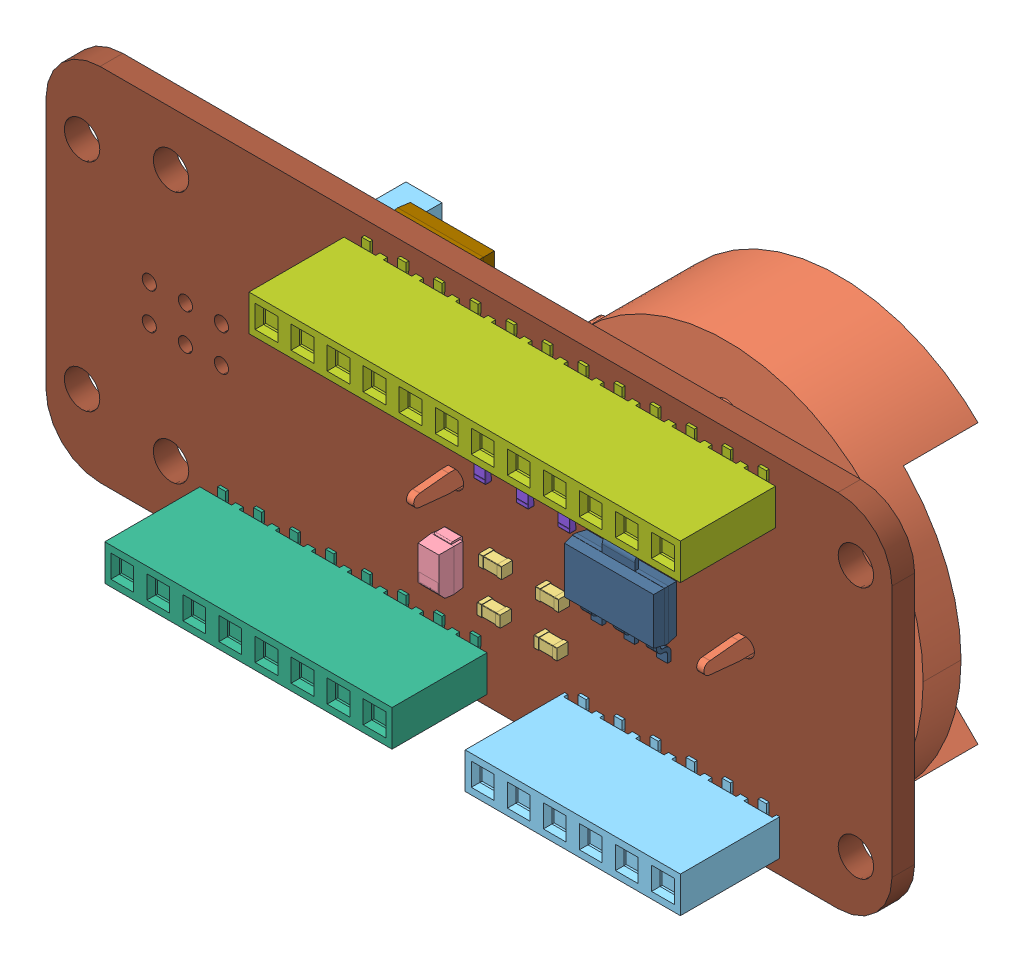
SolidWorks assembly p21014, configuration Default. Lengths in mm.
Overall size (59.61 27.76 20.34).
44 component instances, 11 part files, 0 mates.
Components (placement in the parent):
- p21014.step-1: p21014.step [Default] at origin size (59.61 27.76 20.34)
  - LED_0805_2012Metric.step-1: LED_0805_2012Metric.step [Default] at (193.91 -69.95 -0.05) x (1 0 0) z (0 0 -1) size (2 1.25 1.1)
    - SOLID.step-1: SOLID.step [Default] at origin size (2 1.25 1.1)
  - keystone-PN1027.step-1: keystone-PN1027.step [Default] at (211 -60.16 -2.55) x (0 1 0) z (-1 0 0) size (27.76 16.03 30.96)
    - SOLID-0.step-1: SOLID-0.step [Default] at origin size (27.76 16.03 30.96)
  - C_0603_1608Metric.step-1: C_0603_1608Metric.step [Default] at (203.265 -66.415 1.65) size (1.6 0.8 0.8)
    - SOLID-1.step-1: SOLID-1.step [Default] at origin size (1.6 0.8 0.8)
  - C_0603_1608Metric.step-2: C_0603_1608Metric.step [Default] at (203.365 -63.405 1.65) size (1.6 0.8 0.8)
    - SOLID-1.step-1: SOLID-1.step [Default] at origin size (1.6 0.8 0.8)
  - C_0603_1608Metric.step-3: C_0603_1608Metric.step [Default] at (199.255 -66.415 1.65) size (1.6 0.8 0.8)
    - SOLID-1.step-1: SOLID-1.step [Default] at origin size (1.6 0.8 0.8)
  - C_0603_1608Metric.step-4: C_0603_1608Metric.step [Default] at (199.355 -63.405 1.65) size (1.6 0.8 0.8)
    - SOLID-1.step-1: SOLID-1.step [Default] at origin size (1.6 0.8 0.8)
  - CP_EIA-3216-18_Kemet-A.step-1: CP_EIA-3216-18_Kemet-A.step [Default] at (196.02 -64.89 1.65) x (0 1 0) z (0 0 1) size (3.2 1.6 1.8)
    - SOLID-2.step-1: SOLID-2.step [Default] at origin size (3.2 1.6 1.8)
  - LED_0805_2012Metric.step-2: LED_0805_2012Metric.step [Default] at (190.44 -70.04 -0.05) x (0 1 0) z (0 0 -1) size (2 1.25 1.1)
    - SOLID.step-1: SOLID.step [Default] at origin size (2 1.25 1.1)
  - 91601-306LFc.step-1: 91601-306LFc.step [Default] at (185 -60.16 -7.25) x (0 -1 0) z (1 0 0) size (15.16 7.2 3.19)
    - SOLID-3.step-1: SOLID-3.step [Default] at origin size (15.16 7.2 3.19)
  - 91601-308LFc.step-1: 91601-308LFc.step [Default] at (188.73 -70.32 8.85) x (1 0 0) z (0 -1 0) size (20.24 7.2 3.19)
    - SOLID-4.step-1: SOLID-4.step [Default] at origin size (20.24 7.2 3.19)
  - 91601-412ALFc.step-1: 91601-412ALFc.step [Default] at (203.97 -50 8.85) x (1 0 0) z (0 -1 0) size (30.4 7.2 3.19)
    - SOLID-5.step-1: SOLID-5.step [Default] at origin size (30.4 7.2 3.19)
  - 91601-306LFc.step-2: 91601-306LFc.step [Default] at (211.59 -70.32 8.85) x (1 0 0) z (0 -1 0) size (15.16 7.2 3.19)
    - SOLID-3.step-1: SOLID-3.step [Default] at origin size (15.16 7.2 3.19)
  - R_0603_1608Metric.step-1: R_0603_1608Metric.step [Default] at (198.265 -58.125 1.65) x (0 1 0) z (0 0 1) size (1.6 0.8 0.45)
    - SOLID-6.step-1: SOLID-6.step [Default] at origin size (1.6 0.8 0.45)
  - R_0603_1608Metric.step-2: R_0603_1608Metric.step [Default] at (195.165 -54.115 1.65) x (0 1 0) z (0 0 1) size (1.6 0.8 0.45)
    - SOLID-6.step-1: SOLID-6.step [Default] at origin size (1.6 0.8 0.45)
  - R_0603_1608Metric.step-3: R_0603_1608Metric.step [Default] at (204.21 -54.11 1.65) x (0 1 0) z (0 0 1) size (1.6 0.8 0.45)
    - SOLID-6.step-1: SOLID-6.step [Default] at origin size (1.6 0.8 0.45)
  - R_0603_1608Metric.step-4: R_0603_1608Metric.step [Default] at (201.27 -58.12 1.65) x (0 1 0) z (0 0 1) size (1.6 0.8 0.45)
    - SOLID-6.step-1: SOLID-6.step [Default] at origin size (1.6 0.8 0.45)
  - R_0603_1608Metric.step-5: R_0603_1608Metric.step [Default] at (201.27 -54.09 1.65) x (0 1 0) z (0 0 1) size (1.6 0.8 0.45)
    - SOLID-6.step-1: SOLID-6.step [Default] at origin size (1.6 0.8 0.45)
  - R_0603_1608Metric.step-6: R_0603_1608Metric.step [Default] at (198.265 -54.115 1.65) x (0 1 0) z (0 0 1) size (1.6 0.8 0.45)
    - SOLID-6.step-1: SOLID-6.step [Default] at origin size (1.6 0.8 0.45)
  - R_0603_1608Metric.step-7: R_0603_1608Metric.step [Default] at (204.21 -58.135 1.65) x (0 1 0) z (0 0 1) size (1.6 0.8 0.45)
    - SOLID-6.step-1: SOLID-6.step [Default] at origin size (1.6 0.8 0.45)
  - CP_EIA-6032-15_Kemet-U.step-1: CP_EIA-6032-15_Kemet-U.step [Default] at (192.7 -49.67 -0.05) x (1 0 0) z (0 0 -1) size (6.3 3.5 1.5)
    - SOLID-7.step-1: SOLID-7.step [Default] at origin size (6.3 3.5 1.5)
  - SOT-223.step-1: SOT-223.step [Default] at (208.64 -60.08 1.65) x (0 1 0) z (0 0 1) size (7 6.5 1.7)
    - SOLID-8.step-1: SOLID-8.step [Default] at origin size (7 6.5 1.7)
  - COMPOUND.step-1: COMPOUND.step [Default] at origin size (59.61 25.4 1.6)
